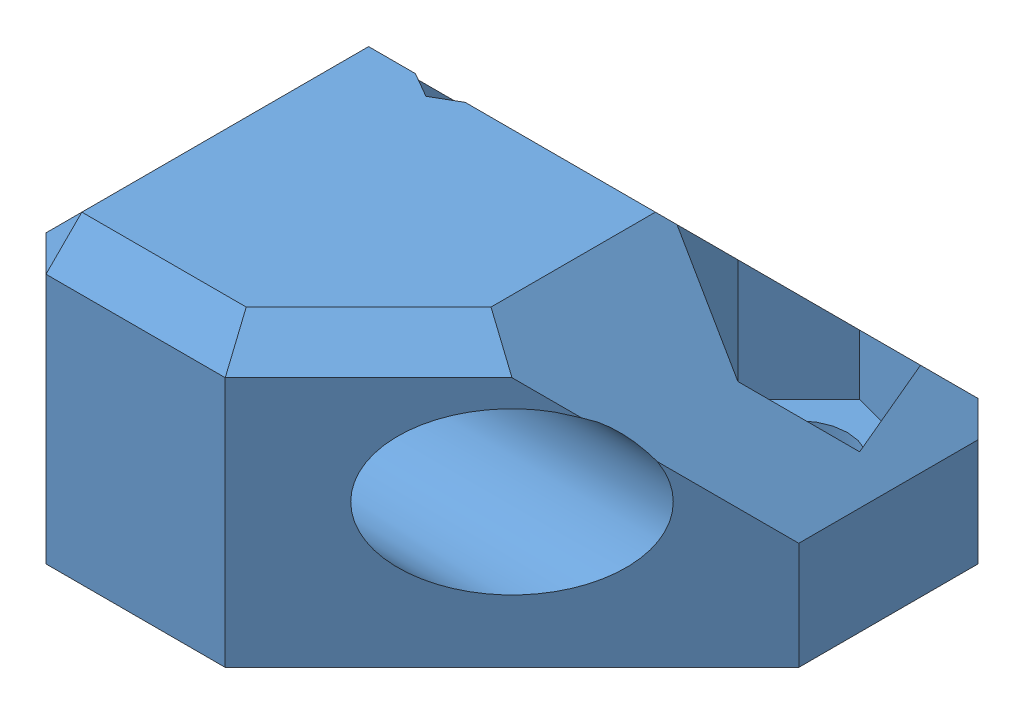
SolidWorks assembly Glareshield Mounting Tab, configuration RH. Lengths in mm.
Overall size (22.62 12.7 22.23).
2 component instances, 2 part files, 11 mates.
Components (placement in the parent):
- Glareshield Mounting Tab-1: Glareshield Mounting Tab [RH] at origin size (22.23 12.7 22.23)
- 93365A160 - INSERT, .25-20, BRASS, FOR PLASTICS-1: 93365A160 - INSERT, .25-20, BRASS, FOR PLASTICS [93365A160] at (-6.35 0 0) x (0 0.07594 0.997112) z (0 -0.997112 0.07594) size (9.53 8.41 9.53)
Mates (geometry in assembly coordinates):
- Coincident1: coincident aligned: plane of Glareshield Mounting Tab-1 through (0 0 0) normal (1 0 0)
- Coincident2: coincident aligned: plane of Glareshield Mounting Tab-1 through (0 0 0) normal (0 1 0)
- Coincident3: coincident aligned: plane of Glareshield Mounting Tab-1 through (0 0 0) normal (0 0 1)
- Concentric1: concentric anti-aligned: cone of Glareshield Mounting Tab-1 through (-6.35 0 0) axis (1 0 0); cylinder of 93365A160 - INSERT, .25-20, BRASS, FOR PLASTICS-1 through (-6.35 0 0) axis (-1 0 0) radius 4.4323
- Coincident4: coincident aligned: plane of Glareshield Mounting Tab-1 through (-6.35 6.35 6.35) normal (-1 0 0); plane of 93365A160 - INSERT, .25-20, BRASS, FOR PLASTICS-1 through (-6.35 0 0) normal (-1 0 0)
- Concentric2: concentric anti-aligned: cone of Glareshield Mounting Tab-1 through (-6.35 0 0) axis (1 0 0); cylinder of 93365A160 - INSERT, .25-20, BRASS, FOR PLASTICS-1 through (-6.35 0 0) axis (-1 0 0) radius 4.4323
- Coincident5: coincident aligned: plane of Glareshield Mounting Tab-1 through (-6.35 6.35 -6.35) normal (-1 0 0); plane of 93365A160 - INSERT, .25-20, BRASS, FOR PLASTICS-1 through (-6.35 0 0) normal (-1 0 0)
- Concentric3: concentric anti-aligned: cone of Glareshield Mounting Tab-1 through (11.1125 -6.35 -11.1125) axis (0 1 0); cylinder of 93365A130 - INSERT, 6-32, BRASS, FOR PLASTICS-1 through (11.1125 -6.35 -11.1125) axis (0 -1 0) radius 2.5273
- Coincident6: coincident aligned: plane of Glareshield Mounting Tab-1 through (0 -6.35 0) normal (0 -1 0); plane of 93365A130 - INSERT, 6-32, BRASS, FOR PLASTICS-1 through (11.1125 -6.35 -11.1125) normal (0 -1 0)
- Concentric4: concentric anti-aligned: cone of Glareshield Mounting Tab-1 through (-1.5875 -6.35 -11.1125) axis (0 1 0); cylinder of 93365A130 - INSERT, 6-32, BRASS, FOR PLASTICS-2 through (-1.5875 -6.35 -11.1125) axis (0 -1 0) radius 2.5273
- Coincident7: coincident aligned: plane of Glareshield Mounting Tab-1 through (0 -6.35 0) normal (0 -1 0); plane of 93365A130 - INSERT, 6-32, BRASS, FOR PLASTICS-2 through (-1.5875 -6.35 -11.1125) normal (0 -1 0)
